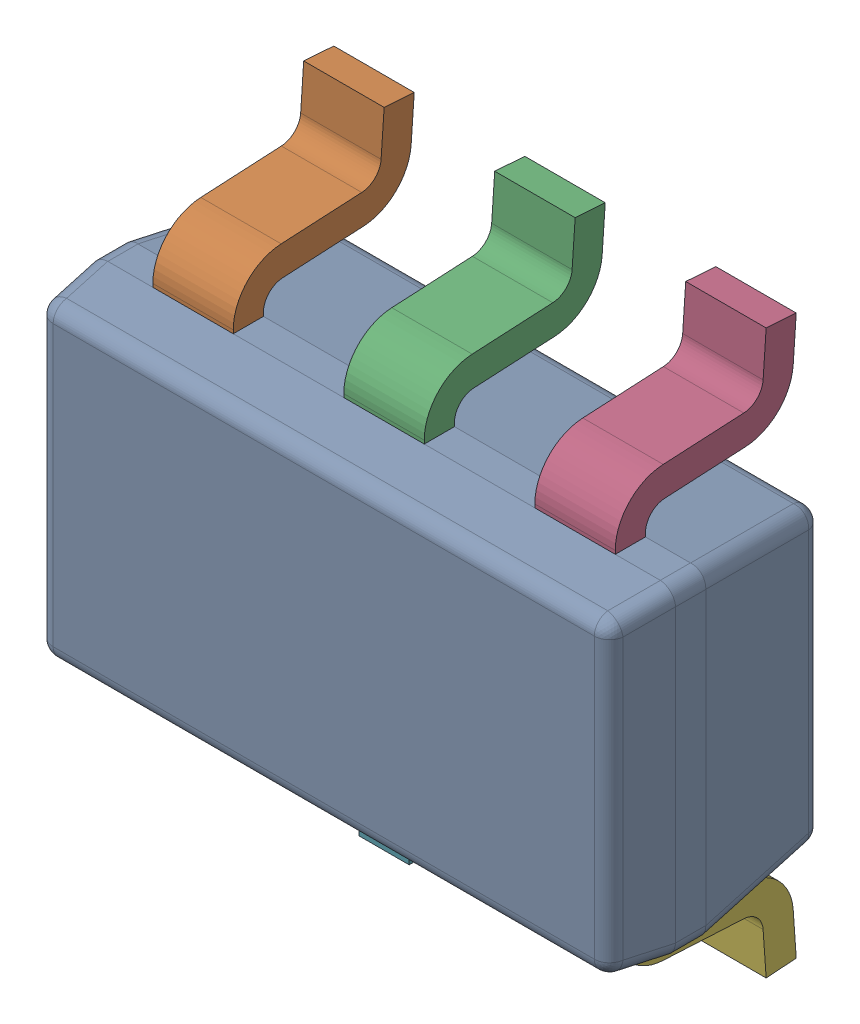
SolidWorks assembly IC4_1.step, configuration Default. Lengths in mm.
Overall size (2.9 2.8 1.2).
8 component instances, 3 part files, 0 mates.
Components (placement in the parent):
- 6348792768_1.step-11: 6348792768_1.step [Default] at (439.713 284.778 0) x (0 -1 0) z (0 0 1) size (2.8 2.9 1.2)
  - BODY-SOT-1213_1.step-11: BODY-SOT-1213_1.step [Default] at (0 0 0.9) x (0 -1 0) z (-1 0 0) size (2.9 1.1 1.6)
  - LEAD-SOT-1214_1.step-85: LEAD-SOT-1214_1.step [Default] at (-0.9395 -0.95 0.25) x (0 -1 0) z (-1 0 0) size (0.4 0.9 0.6)
  - LEAD-SOT-1214_1.step-86: LEAD-SOT-1214_1.step [Default] at (-0.9395 0 0.25) x (0 -1 0) z (-1 0 0) size (0.4 0.9 0.6)
  - LEAD-SOT-1214_1.step-87: LEAD-SOT-1214_1.step [Default] at (-0.9395 0.95 0.25) x (0 -1 0) z (-1 0 0) size (0.4 0.9 0.6)
  - LEAD-SOT-1214_1.step-88: LEAD-SOT-1214_1.step [Default] at (0.9395 -0.95 0.25) x (0 1 0) z (1 0 0) size (0.4 0.9 0.6)
  - LEAD-SOT-1214_1.step-89: LEAD-SOT-1214_1.step [Default] at (0.9395 0.95 0.25) x (0 1 0) z (1 0 0) size (0.4 0.9 0.6)
  - LEAD-DUMMY-1215_1.step-11: LEAD-DUMMY-1215_1.step [Default] at (1.05 0 0.76) x (0 -1 0) z (-1 0 0) size (0.25 0.14 0.25)
